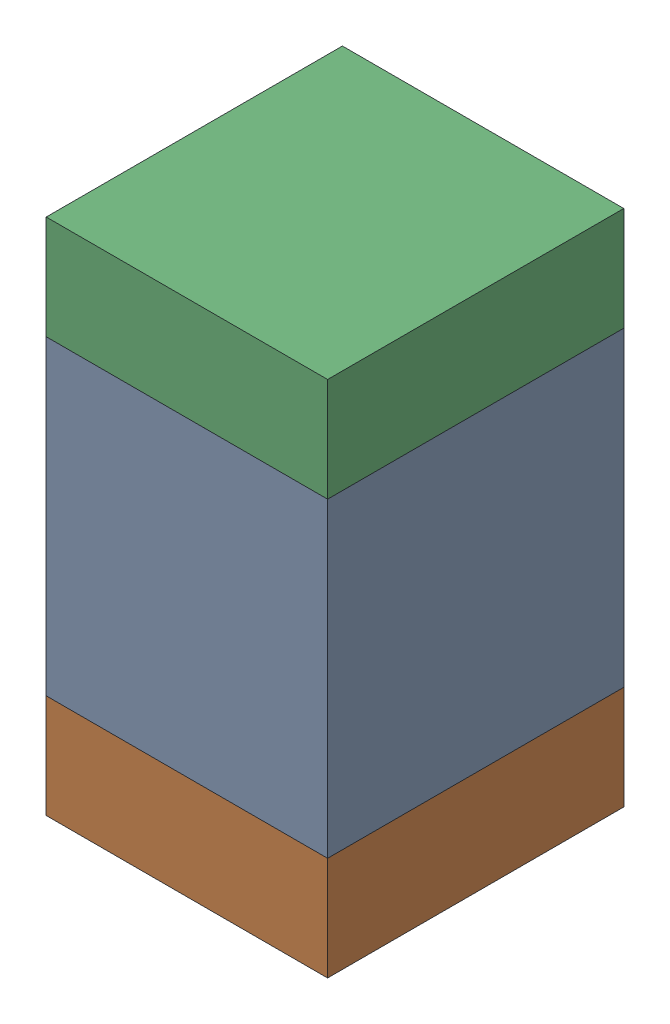
SolidWorks assembly C9-1, configuration Default. Lengths in mm.
Overall size (0.95 1.75 1).
6 component instances, 2 part files, 0 mates.
Components (placement in the parent):
- 959208528-1-1: 959208528-1 [Default] at (108.577 76.835 0) size (0.95 1.05 1)
  - Extruded-46-1: Extruded-46 [Default] at origin size (0.95 1.05 1)
- 959208664-1-1: 959208664-1 [Default] at (108.577 76.135 0) size (0.95 0.35 1)
  - Extruded-45-1: Extruded-45 [Default] at origin size (0.95 0.35 1)
- 959208664-1-2: 959208664-1 [Default] at (108.577 77.535 0) size (0.95 0.35 1)
  - Extruded-45-1: Extruded-45 [Default] at origin size (0.95 0.35 1)
